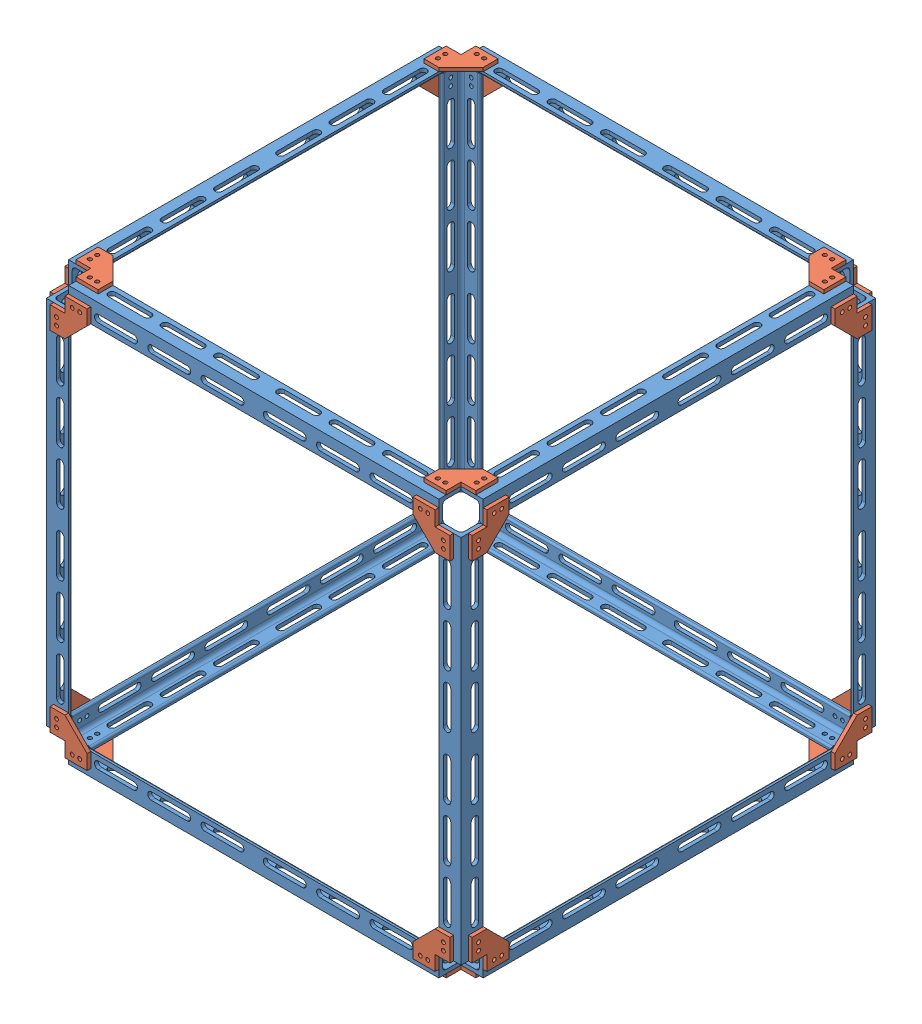
SolidWorks assembly Outer struct 14 in side length, configuration Default. Lengths in mm.
Overall size (361.95 361.95 361.95).
36 component instances, 2 part files, 55 mates.
Components (placement in the parent):
- WIP 14 inch .75 L rod-1: WIP 14 inch .75 L rod [8982K281] at (-9.525 9.525 0) size (19.05 19.05 317.5)
- WIP bracket for .75 L bar-1: WIP bracket for .75 L bar [Default] at (-44.45 -3.175 -171.45) size (31.75 3.17 31.75)
- WIP 14 inch .75 L rod-2: WIP 14 inch .75 L rod [8982K281] at (-177.8 9.525 -168.275) x (0 0 -1) z (1 0 0) size (19.05 19.05 317.5)
- WIP 14 inch .75 L rod-3: WIP 14 inch .75 L rod [8982K281] at (-9.525 177.8 -168.275) x (1 0 0) z (0 -1 0) size (19.05 19.05 317.5)
- WIP bracket for .75 L bar-2: WIP bracket for .75 L bar [Default] at (0 44.45 -171.45) x (0 -1 0) z (0 0 1) size (31.75 3.17 31.75)
- WIP bracket for .75 L bar-3: WIP bracket for .75 L bar [Default] at (-44.45 6.35 -177.8) x (1 0 0) z (0 1 0) size (31.75 3.17 31.75)
- WIP bracket for .75 L bar-4: WIP bracket for .75 L bar [Default] at (-311.15 349.25 -177.8) x (-1 0 0) z (0 -1 0) size (31.75 3.17 31.75)
- WIP bracket for .75 L bar-5: WIP bracket for .75 L bar [Default] at (-355.6 311.15 -171.45) x (0 1 0) z (0 0 1) size (31.75 3.17 31.75)
- WIP bracket for .75 L bar-6: WIP bracket for .75 L bar [Default] at (-311.15 358.775 -171.45) x (-1 0 0) z (0 0 1) size (31.75 3.17 31.75)
- WIP 14 inch .75 L rod-4: WIP 14 inch .75 L rod [8982K281] at (-177.8 346.075 -168.275) x (0 0 -1) z (-1 0 0) size (19.05 19.05 317.5)
- WIP 14 inch .75 L rod-5: WIP 14 inch .75 L rod [8982K281] at (-346.075 346.075 0) x (-1 0 0) z (0 0 1) size (19.05 19.05 317.5)
- WIP 14 inch .75 L rod-6: WIP 14 inch .75 L rod [8982K281] at (-346.075 177.8 -168.275) x (-1 0 0) z (0 1 0) size (19.05 19.05 317.5)
- WIP bracket for .75 L bar-8: WIP bracket for .75 L bar [Default] at (-6.35 311.15 -177.8) x (0 1 0) z (-1 0 0) size (31.75 3.17 31.75)
- WIP bracket for .75 L bar-9: WIP bracket for .75 L bar [Default] at (-349.25 44.45 -177.8) x (0 -1 0) z (1 0 0) size (31.75 3.17 31.75)
- WIP bracket for .75 L bar-11: WIP bracket for .75 L bar [Default] at (-6.35 355.6 133.35) x (0 0 1) z (-1 0 0) size (31.75 3.17 31.75)
- WIP bracket for .75 L bar-12: WIP bracket for .75 L bar [Default] at (-44.45 349.25 177.8) x (1 0 0) z (0 -1 0) size (31.75 3.17 31.75)
- WIP 14 inch .75 L rod-7: WIP 14 inch .75 L rod [8982K281] at (-177.8 346.075 168.275) x (0 0 1) z (1 0 0) size (19.05 19.05 317.5)
- WIP 14 inch .75 L rod-8: WIP 14 inch .75 L rod [8982K281] at (-9.525 346.075 0) x (0 1 0) z (0 0 1) size (19.05 19.05 317.5)
- WIP bracket for .75 L bar-13: WIP bracket for .75 L bar [Default] at (3.175 349.25 133.35) x (0 0 1) z (0 -1 0) size (31.75 3.17 31.75)
- WIP 14 inch .75 L rod-9: WIP 14 inch .75 L rod [8982K281] at (-9.525 177.8 168.275) x (0 0 1) z (0 -1 0) size (19.05 19.05 317.5)
- WIP bracket for .75 L bar-14: WIP bracket for .75 L bar [Default] at (3.175 311.15 -171.45) x (0 1 0) z (0 0 1) size (31.75 3.17 31.75)
- WIP bracket for .75 L bar-15: WIP bracket for .75 L bar [Default] at (-349.25 358.775 133.35) x (0 0 1) z (1 0 0) size (31.75 3.17 31.75)
- WIP bracket for .75 L bar-16: WIP bracket for .75 L bar [Default] at (-44.45 355.6 -171.45) size (31.75 3.17 31.75)
- WIP bracket for .75 L bar-17: WIP bracket for .75 L bar [Default] at (-6.35 -3.175 133.35) x (0 0 1) z (-1 0 0) size (31.75 3.17 31.75)
- WIP bracket for .75 L bar-18: WIP bracket for .75 L bar [Default] at (3.175 44.45 171.45) x (0 -1 0) z (0 0 -1) size (31.75 3.17 31.75)
- WIP bracket for .75 L bar-19: WIP bracket for .75 L bar [Default] at (-349.25 311.15 177.8) x (0 1 0) z (1 0 0) size (31.75 3.17 31.75)
- WIP bracket for .75 L bar-20: WIP bracket for .75 L bar [Default] at (-355.6 349.25 133.35) x (0 0 1) z (0 -1 0) size (31.75 3.17 31.75)
- WIP bracket for .75 L bar-21: WIP bracket for .75 L bar [Default] at (-355.6 44.45 171.45) x (0 -1 0) z (0 0 -1) size (31.75 3.17 31.75)
- WIP 14 inch .75 L rod-11: WIP 14 inch .75 L rod [8982K281] at (-346.075 177.8 168.275) x (-1 0 0) z (0 -1 0) size (19.05 19.05 317.5)
- WIP bracket for .75 L bar-22: WIP bracket for .75 L bar [Default] at (-311.15 6.35 177.8) x (-1 0 0) z (0 1 0) size (31.75 3.17 31.75)
- WIP 14 inch .75 L rod-12: WIP 14 inch .75 L rod [8982K281] at (-177.8 9.525 168.275) x (0 0 1) z (-1 0 0) size (19.05 19.05 317.5)
- WIP bracket for .75 L bar-23: WIP bracket for .75 L bar [Default] at (-311.15 -3.175 171.45) x (-1 0 0) z (0 0 -1) size (31.75 3.17 31.75)
- WIP 14 inch .75 L rod-13: WIP 14 inch .75 L rod [8982K281] at (-346.075 9.525 0) x (-1 0 0) z (0 0 -1) size (19.05 19.05 317.5)
- WIP bracket for .75 L bar-24: WIP bracket for .75 L bar [Default] at (-355.6 6.35 -133.35) x (0 0 -1) z (0 1 0) size (31.75 3.17 31.75)
- WIP bracket for .75 L bar-25: WIP bracket for .75 L bar [Default] at (-349.25 -3.175 -133.35) x (0 0 -1) z (1 0 0) size (31.75 3.17 31.75)
- WIP bracket for .75 L bar-26: WIP bracket for .75 L bar [Default] at (-6.35 44.45 177.8) x (0 -1 0) z (-1 0 0) size (31.75 3.17 31.75)
Mates (geometry in assembly coordinates):
- Coincident45: coincident anti-aligned: circle of WIP .75 L rod-2; circle of WIP bracket for .75 L bar-3
- Coincident46: coincident anti-aligned: circle of WIP .75 L rod-3; circle of WIP bracket for .75 L bar-3
- Coincident47: coincident aligned: circle of WIP .75 L rod-1; circle of WIP bracket for .75 L bar-1
- Coincident48: coincident aligned: circle of WIP bracket for .75 L bar-1; circle of WIP .75 L rod-2
- Coincident49: coincident anti-aligned: circle of WIP .75 L rod-1; circle of WIP bracket for .75 L bar-2
- Coincident50: coincident anti-aligned: circle of WIP .75 L rod-3; circle of WIP bracket for .75 L bar-2
- Coincident51: coincident anti-aligned: circle of WIP .75 L rod-6; circle of WIP bracket for .75 L bar-9
- Coincident52: coincident aligned: circle of WIP bracket for .75 L bar-6; circle of WIP .75 L rod-5
- Coincident53: coincident aligned: circle of WIP bracket for .75 L bar-6; circle of WIP .75 L rod-4
- Coincident54: coincident anti-aligned: circle of WIP bracket for .75 L bar-4; circle of WIP .75 L rod-4
- Coincident55: coincident anti-aligned: circle of WIP bracket for .75 L bar-4; circle of WIP .75 L rod-6
- Coincident56: coincident anti-aligned: circle of WIP bracket for .75 L bar-5; circle of WIP .75 L rod-6
- Coincident57: coincident anti-aligned: circle of WIP bracket for .75 L bar-5; circle of WIP .75 L rod-5
- Coincident58: coincident aligned: circle of WIP bracket for .75 L bar-6; circle of WIP .75 L rod-5
- Coincident59: coincident aligned: circle of WIP bracket for .75 L bar-6; circle of WIP .75 L rod-4
- Coincident61: coincident anti-aligned: circle of WIP .75 L rod-2; circle of WIP bracket for .75 L bar-9
- Coincident62: coincident anti-aligned: circle of WIP .75 L rod-4; circle of WIP bracket for .75 L bar-8
- Coincident63: coincident anti-aligned: circle of WIP .75 L rod-3; circle of WIP bracket for .75 L bar-8
- Coincident64: coincident anti-aligned: circle of WIP bracket for .75 L bar-12; circle of WIP .75 L rod-7
- Coincident65: coincident anti-aligned: circle of WIP bracket for .75 L bar-11; circle of WIP .75 L rod-7
- Coincident66: coincident aligned: circle of WIP .75 L rod-8; circle of WIP bracket for .75 L bar-13
- Coincident67: coincident aligned: circle of WIP bracket for .75 L bar-13; circle of WIP .75 L rod-9
- Coincident68: coincident anti-aligned: circle of WIP bracket for .75 L bar-12; circle of WIP .75 L rod-9
- Coincident69: coincident anti-aligned: circle of WIP bracket for .75 L bar-11; circle of WIP .75 L rod-8
- Coincident70: coincident aligned: circle of WIP .75 L rod-3; circle of WIP bracket for .75 L bar-14
- Coincident71: coincident aligned: circle of WIP .75 L rod-8; circle of WIP bracket for .75 L bar-14
- Coincident72: coincident anti-aligned: circle of WIP .75 L rod-8; circle of WIP bracket for .75 L bar-16
- Coincident73: coincident anti-aligned: circle of WIP .75 L rod-4; circle of WIP bracket for .75 L bar-16
- Coincident74: coincident aligned: circle of WIP .75 L rod-7; circle of WIP bracket for .75 L bar-15
- Coincident76: coincident aligned: circle of WIP .75 L rod-5; circle of WIP bracket for .75 L bar-15
- Coincident77: coincident anti-aligned: circle of WIP .75 L rod-5; circle of WIP bracket for .75 L bar-20
- Coincident78: coincident anti-aligned: circle of WIP .75 L rod-7; circle of WIP bracket for .75 L bar-19
- Coincident79: coincident aligned: circle of WIP .75 L rod-1; circle of WIP bracket for .75 L bar-18
- Coincident80: coincident aligned: circle of WIP .75 L rod-9; circle of WIP bracket for .75 L bar-18
- Coincident81: coincident anti-aligned: circle of WIP bracket for .75 L bar-21; circle of WIP .75 L rod-11
- Coincident82: coincident anti-aligned: circle of WIP .75 L rod-11; circle of WIP bracket for .75 L bar-22
- Coincident83: coincident aligned: circle of WIP .75 L rod-12; circle of WIP bracket for .75 L bar-23
- Coincident84: coincident aligned: circle of WIP bracket for .75 L bar-23; circle of WIP .75 L rod-13
- Coincident85: coincident anti-aligned: circle of WIP bracket for .75 L bar-21; circle of WIP .75 L rod-13
- Coincident86: coincident anti-aligned: circle of WIP bracket for .75 L bar-22; circle of WIP .75 L rod-12
- Coincident87: coincident aligned: circle of WIP .75 L rod-1; circle of WIP bracket for .75 L bar-17
- Coincident88: coincident aligned: circle of WIP bracket for .75 L bar-17; circle of WIP .75 L rod-12
- Coincident89: coincident aligned: circle of WIP .75 L rod-13; circle of WIP bracket for .75 L bar-25
- Coincident91: coincident aligned: circle of WIP .75 L rod-2; circle of WIP bracket for .75 L bar-25
- Coincident92: coincident anti-aligned: circle of WIP .75 L rod-6; circle of WIP bracket for .75 L bar-24
- Coincident93: coincident anti-aligned: circle of WIP .75 L rod-13; circle of WIP bracket for .75 L bar-24
- Coincident94: coincident anti-aligned: circle of WIP .75 L rod-12; circle of WIP bracket for .75 L bar-26
- Coincident95: coincident anti-aligned: circle of WIP .75 L rod-9; circle of WIP bracket for .75 L bar-26
- Coincident96: coincident anti-aligned: circle of WIP bracket for .75 L bar-19; circle of WIP .75 L rod-11
- Coincident99: coincident aligned: circle of WIP bracket for .75 L bar-17; circle of WIP .75 L rod-12
- Coincident100: coincident anti-aligned: circle of WIP bracket for .75 L bar-20; circle of WIP .75 L rod-11
- Coincident101: coincident anti-aligned: circle of WIP bracket for .75 L bar-5; circle of WIP .75 L rod-6
- Coincident102: coincident anti-aligned: circle of WIP bracket for .75 L bar-22; circle of WIP .75 L rod-12
- Coincident103: coincident aligned: circle of WIP .75 L rod-1; circle of WIP bracket for .75 L bar-18
- Coincident104: coincident anti-aligned: circle of WIP bracket for .75 L bar-20; circle of WIP .75 L rod-11
